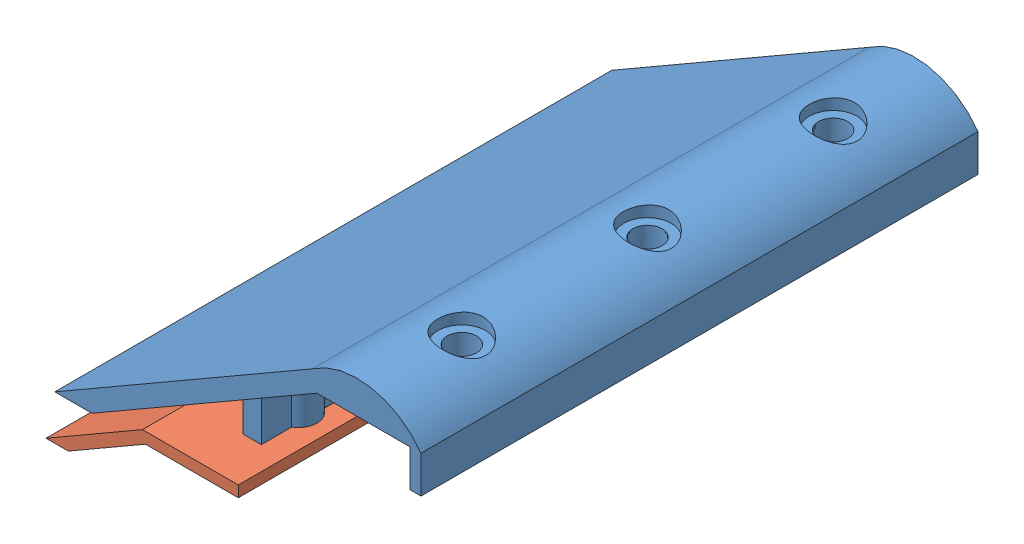
SolidWorks assembly SoportePala, configuration Predeterminado. Lengths in mm.
Overall size (135.72 55.88 150).
2 component instances, 2 part files, 3 mates.
Components (placement in the parent):
- pala2-1: pala2 [Predeterminado] at (85.8775 17.5121 150) size (98.62 43.88 150)
- protecto pala-1: protecto pala [Predeterminado] at (39.6775 -17.4879 150) size (110.9 15 150)
Mates (geometry in assembly coordinates):
- Concéntrica3: concentric: cylinder of pala2-1 through (55.8775 -4.4879 200) axis (0 -1 0) radius 1; circle of protecto pala-1
- Concéntrica4: concentric: cylinder of pala2-1 through (55.8775 -4.4879 100) axis (0 -1 0) radius 1; cylinder of protecto pala-1 through (55.8775 -14.4879 100) axis (0 1 0) radius 1.8986
- Coincidente1: coincident anti-aligned: plane of pala2-1 through (55.8775 -14.4879 100) normal (0 -1 0); plane of protecto pala-1 through (64.6775 -14.4879 225) normal (0 1 0)
